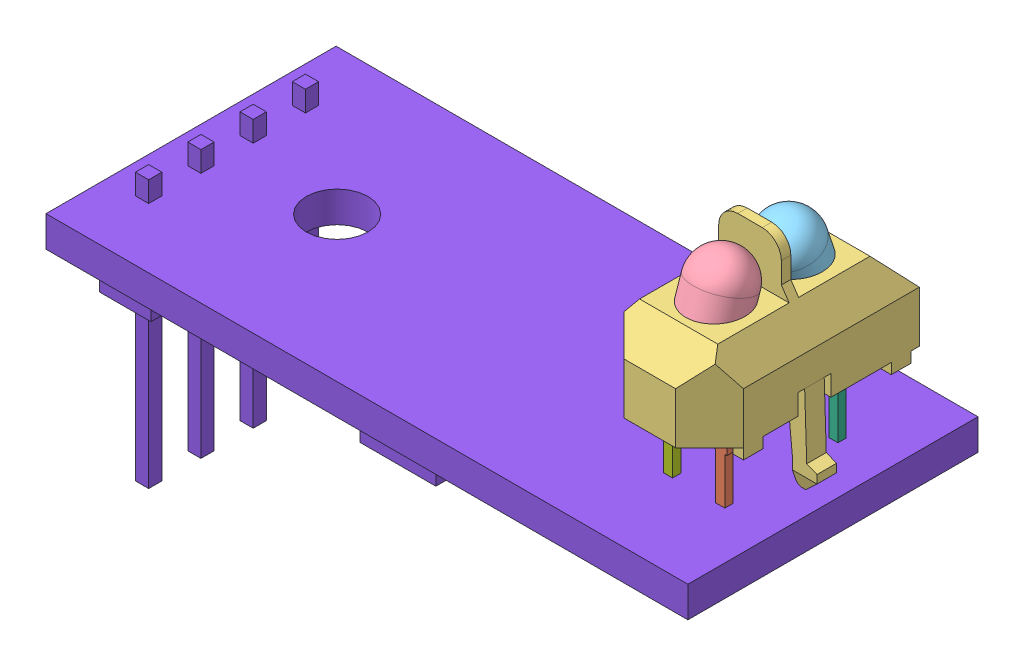
SolidWorks assembly LineSensorAssy.step, configuration Default. Lengths in mm.
Overall size (31.2 22 14.1).
9 component instances, 8 part files, 0 mates.
Components (placement in the parent):
- TCRT5000 v1 _1_.step-1: TCRT5000 v1 _1_.step [Default] at origin size (7 10.52 10.2)
  - Metal Contacts.step-1: Metal Contacts.step [Default] at (12.6357 54.4036 8.3901) size (0.65 4.01 0.4)
  - Metal Contacts-0.step-1: Metal Contacts-0.step [Default] at (12.6357 54.4036 8.3901) size (0.65 4.01 0.4)
  - TCRT5000 v1.step-1: TCRT5000 v1.step [Default] at (12.6357 54.4036 8.3901) size (7 10.02 10.2)
  - LEDs.step-1: LEDs.step [Default] at (12.6357 54.4036 8.3901) size (2.8 2.98 3.1)
  - LEDs-1.step-1: LEDs-1.step [Default] at (12.6357 54.4036 8.3901) size (2.8 2.98 3.1)
  - Metal Contacts-2.step-1: Metal Contacts-2.step [Default] at (12.6357 54.4036 8.3901) size (0.65 4.01 0.4)
  - Metal Contacts-3.step-1: Metal Contacts-3.step [Default] at (12.6357 54.4036 8.3901) size (0.65 4.01 0.4)
- Part 1.step-1: Part 1.step [Default] at (-14.7643 49.9236 1.3401) x (1 0 0) z (0 -1 0) size (31.2 14.1 13)
